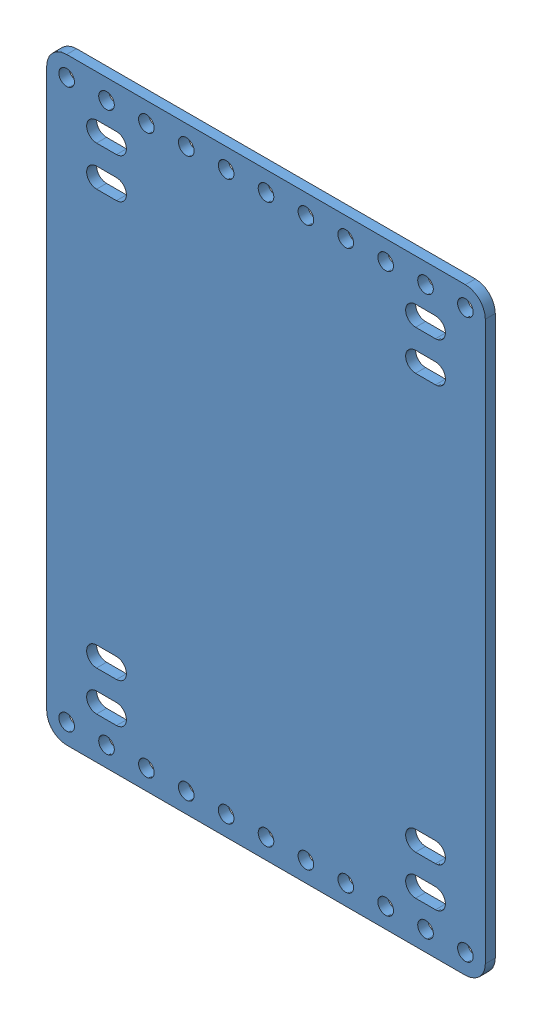
SolidWorks assembly RoboRio Assembly V2, configuration Default. Lengths in mm.
Overall size (146.15 190.5 3.18).
2 component instances, 2 part files, 0 mates.
Components (placement in the parent):
- RoboRIO Board V2-1: RoboRIO Board V2 [Default] at (400.5794 -44.0531 126.3958) size (139.7 190.5 3.17)
- RoboRIO2-1: RoboRIO2 [Default] at (5.4278 92.3556 94.1336) x (0 1 0) z (0 0 1) (suppressed, hidden)
